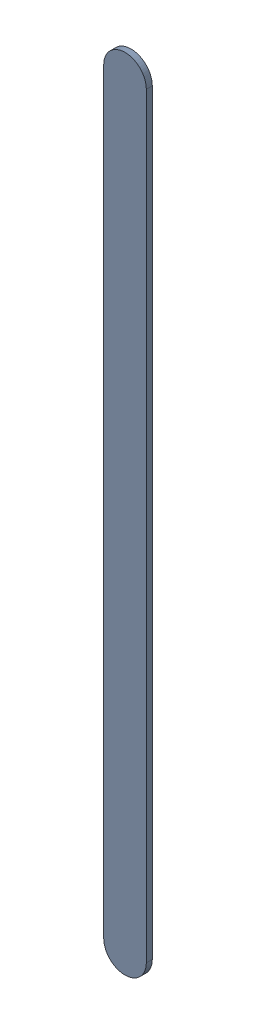
SolidWorks assembly Track (27.878mm,8.518mm)(27.878mm,13.028mm) on Top Layer, configuration Predeterminado. Lengths in mm.
Overall size (0.25 4.76 0.04).
2 component instances, 1 part files, 0 mates.
Components (placement in the parent):
- Track (27.878mm,8.518mm)(27.878mm,13.028mm) on Top Layer-1-1: Track (27.878mm,8.518mm)(27.878mm,13.028mm) on Top Layer-1 [Predeterminado] at (-68.317 -44.187 -0.0457) size (0.25 4.76 0.04)
  - Track (27.878mm,8.518mm)(27.878mm,13.028mm) on Top Layer-Part-1-1: Track (27.878mm,8.518mm)(27.878mm,13.028mm) on Top Layer-Part-1 [Predeterminado] at origin size (0.25 4.76 0.04)
